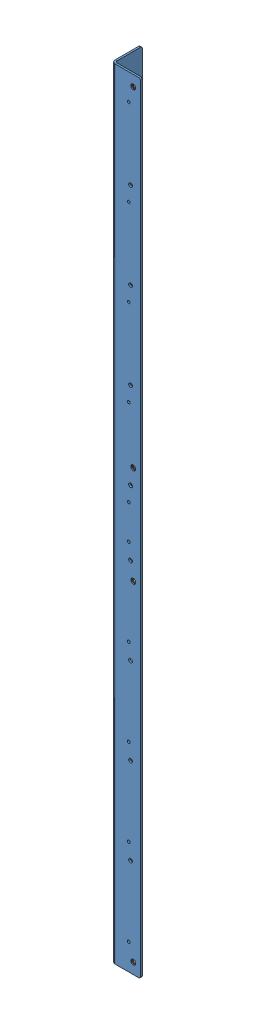
SolidWorks assembly GE-25109, configuration Default. Lengths in mm.
Overall size (50.8 1371.6 50.8).
5 component instances, 3 part files, 7 mates.
Components (placement in the parent):
- GE-25109-01-1: GE-25109-01 [Default] at (0 -1371.6 0) size (50.8 1371.6 50.8)
- pem_clinchnut_.25_20_.054-1: pem_clinchnut_.25_20_.054 [Default] at (38.1 -19.05 -1.8034) x (0 0 -1) z (1 0 0) size (5.69 11.18 11.18)
- pem_clinchnut_.25_20_.054-2: pem_clinchnut_.25_20_.054 [Default] at (38.1 -599.44 -1.8034) x (0 0 -1) z (1 0 0) size (5.69 11.18 11.18)
- Mirrorpem_clinchnut_.25_20_.054-5: Mirrorpem_clinchnut_.25_20_.054 [Default] at (38.1 -1352.55 -1.8034) x (0 0 -1) z (-1 0 0) size (5.69 11.18 11.18)
- Mirrorpem_clinchnut_.25_20_.054-6: Mirrorpem_clinchnut_.25_20_.054 [Default] at (38.1 -772.16 -1.8034) x (0 0 -1) z (-1 0 0) size (5.69 11.18 11.18)
Mates (geometry in assembly coordinates):
- Coincident40: coincident anti-aligned: plane of pem_clinchnut_.25_20_.054-1 through (40.894 -19.05 -3.175) normal (0 0 1); plane of GE-25109-01-1 through (0 0 -3.175) normal (0 0 -1)
- Concentric35: concentric anti-aligned: cylinder of pem_clinchnut_.25_20_.054-1 through (38.1 -19.05 -5.1664) axis (0 0 -1) radius 5.588; cylinder of GE-25109-01-1 through (38.1 -19.05 0) axis (0 0 1) radius 4.3656
- Coincident39: coincident anti-aligned: plane of pem_clinchnut_.25_20_.054-2 through (40.894 -599.44 -3.175) normal (0 0 1); plane of GE-25109-01-1 through (0 0 -3.175) normal (0 0 -1)
- Concentric34: concentric anti-aligned: cylinder of pem_clinchnut_.25_20_.054-2 through (38.1 -599.44 -5.1664) axis (0 0 -1) radius 5.588; cylinder of GE-25109-01-1 through (38.1 -599.44 0) axis (0 0 1) radius 4.3656
- Coincident41: coincident aligned: plane of GE-25109-01-1 through (0 0 0) normal (0 0 1)
- Coincident42: coincident anti-aligned: plane of GE-25109-01-1 through (0 0 0) normal (-1 0 0)
- Coincident43: coincident aligned: plane of GE-25109-01-1 through (6.35 0 -6.35) normal (0 1 0)
